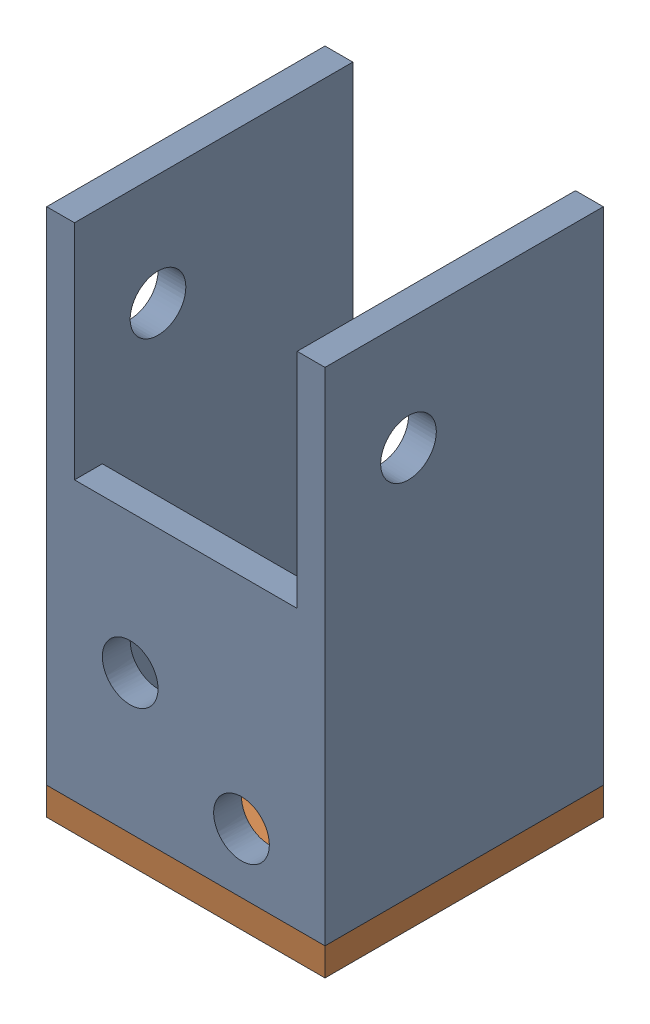
SolidWorks assembly CR25-402, configuration Default. Lengths in mm.
Overall size (31.75 60.32 31.75).
2 component instances, 2 part files, 6 mates.
Components (placement in the parent):
- CR2025-402-01-1: CR2025-402-01 [Default] at origin size (31.75 57.15 31.75)
- CR2025-402-02-1: CR2025-402-02 [Default] at (0 -3.175 0) size (31.75 3.17 31.75)
Mates (geometry in assembly coordinates):
- Coincident1: coincident anti-aligned: plane of CR2025-402-01-1 through (0 0 0) normal (0 -1 0); plane of CR2025-402-02-1 through (0 0 0) normal (0 1 0)
- Coincident2: coincident aligned: plane of CR2025-402-01-1 through (31.75 57.15 0) normal (1 0 0); plane of CR2025-402-02-1 through (31.75 0 0) normal (1 0 0)
- Coincident3: coincident aligned: plane of CR2025-402-01-1 through (0 57.15 0) normal (0 0 1); plane of CR2025-402-02-1 through (0 0 0) normal (0 0 1)
- Coincident4: coincident aligned: plane of CR2025-402-01-1 through (0 0 0) normal (0 0 1)
- Coincident5: coincident aligned: plane of CR2025-402-01-1 through (0 0 0) normal (0 1 0)
- Coincident6: coincident aligned: plane of CR2025-402-01-1 through (0 0 0) normal (1 0 0)
